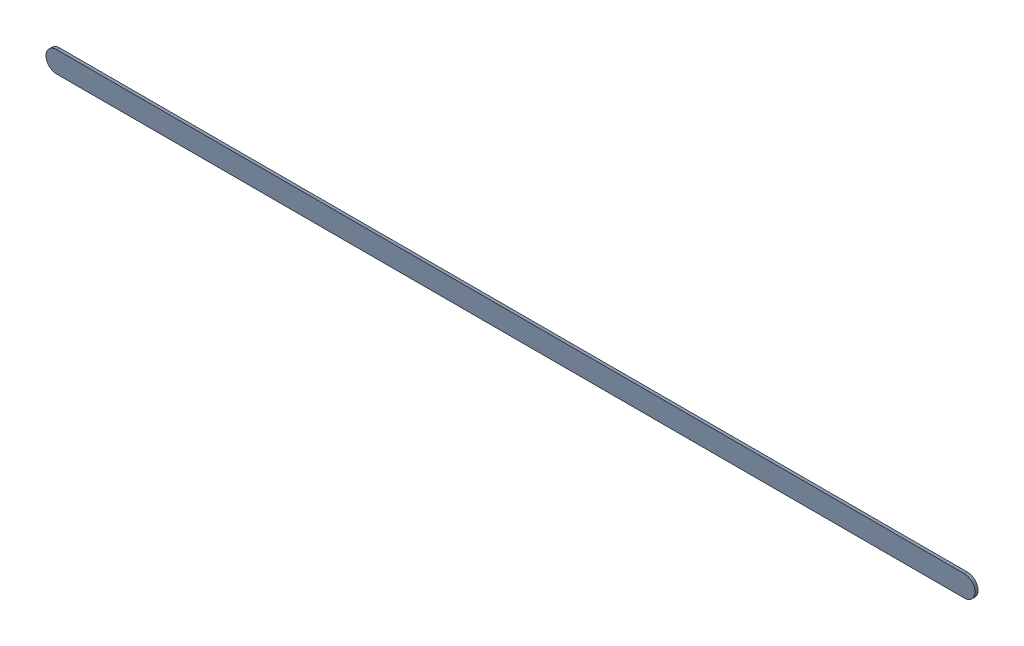
SolidWorks assembly Track (15.521mm,61.2mm)(26.416mm,61.2mm) on Bottom Layer, configuration Predeterminado. Lengths in mm.
Overall size (11.15 0.25 0.04).
2 component instances, 1 part files, 0 mates.
Components (placement in the parent):
- Track (15.521mm,61.2mm)(26.416mm,61.2mm) on Bottom Layer-1-1: Track (15.521mm,61.2mm)(26.416mm,61.2mm) on Bottom Layer-1 [Predeterminado] at (-68.317 -44.187 -0.4013) size (11.15 0.25 0.04)
  - Track (15.521mm,61.2mm)(26.416mm,61.2mm) on Bottom Layer-Part-1-1: Track (15.521mm,61.2mm)(26.416mm,61.2mm) on Bottom Layer-Part-1 [Predeterminado] at origin size (11.15 0.25 0.04)
